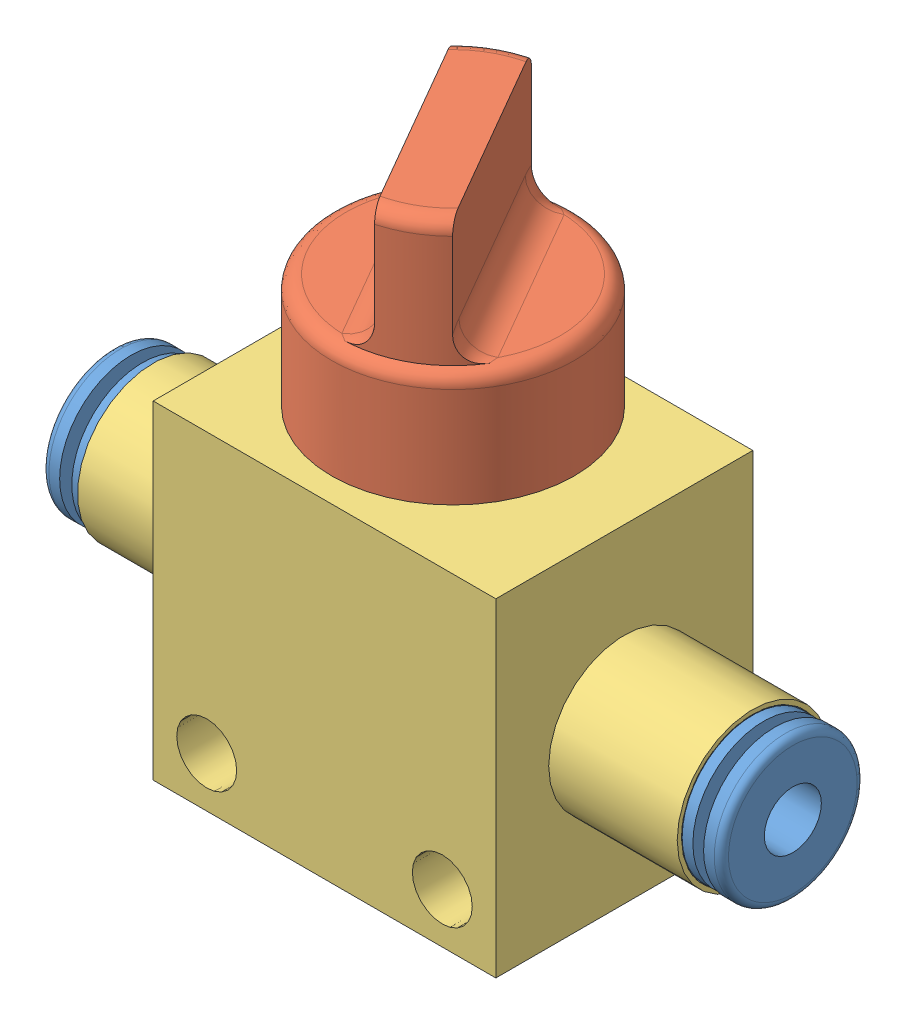
SolidWorks assembly VHK3-04F-04F, configuration Default. Lengths in mm.
Overall size (47.61 41 18).
4 component instances, 3 part files, 0 mates.
Components (placement in the parent):
- VHK3-04F-04F.step_VHK Fittings_04-1: VHK3-04F-04F.step_VHK Fittings_04 [Default] at (-8 0 0) x (0 0 1) z (-1 0 0) size (10 10 15.8)
- VHK3-04F-04F.step_VHK Knob_Std-1: VHK3-04F-04F.step_VHK Knob_Std [Default] at (0 13.2 0) size (17.03 16.8 17.03)
- VHK3-04F-04F.step_VHK Fittings_04-2: VHK3-04F-04F.step_VHK Fittings_04 [Default] at (8 0 0) x (0 0 -1) z (1 0 0) size (10 10 15.8)
- VHK3-04F-04F.step_VHKBody_04F-04F-1: VHK3-04F-04F.step_VHKBody_04F-04F [Default] at origin size (42 24.2 18)
